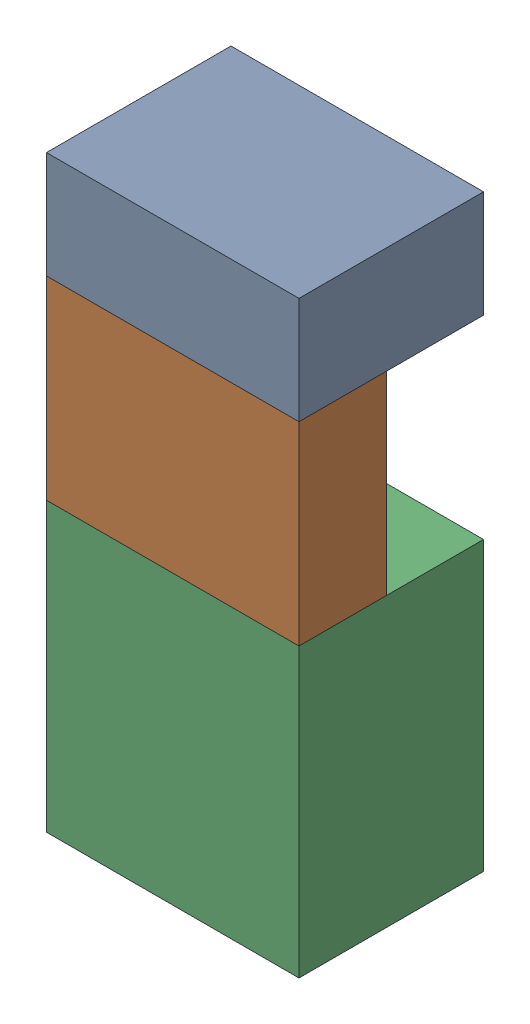
SolidWorks assembly SUP_K13, configuration Default. Lengths in mm.
Overall size (13 30.3 9.5).
6 component instances, 3 part files, 0 mates.
Components (placement in the parent):
- 1151724928-1: 1151724928 [Default] at (194.945 41.975 0) size (13 5.5 9.5)
  - Extruded_2-1: Extruded_2 [Default] at origin size (13 5.5 9.5)
- 1151725064-1: 1151725064 [Default] at (194.945 34.225 5) size (13 10 4.5)
  - Extruded_3-1: Extruded_3 [Default] at origin size (13 10 4.5)
- 1151724792-1: 1151724792 [Default] at (194.945 21.825 0) size (13 14.8 9.5)
  - Extruded_4-1: Extruded_4 [Default] at origin size (13 14.8 9.5)
